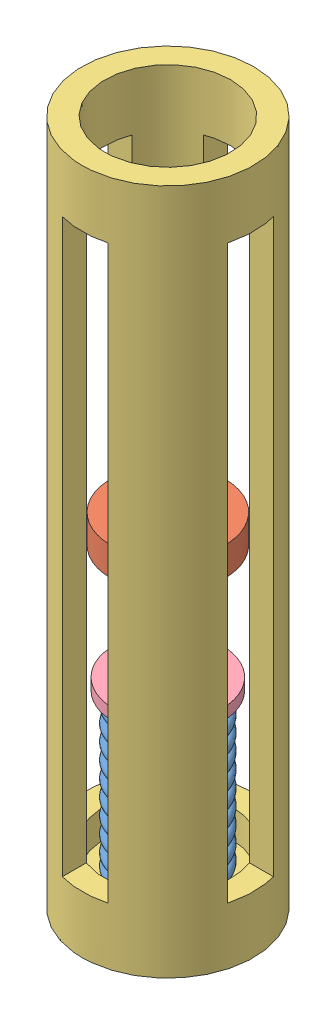
SolidWorks assembly Torpedo Spring Tube 1 inch, configuration Default. Lengths in mm.
Overall size (38.1 152.4 38.1).
4 component instances, 4 part files, 6 mates.
Components (placement in the parent):
- 1986K525_302 STAINLESS STEEL COMPRESSION SPRING-1: 1986K525_302 STAINLESS STEEL COMPRESSION SPRING [1986K525] at (16.8623 -46.4244 245.3297) x (0 0 -1) z (0 -1 0) size (23.69 23.69 38.1)
- MS-P-069 Torpedo Spring Attachment Tube Plunger-1: MS-P-069 Torpedo Spring Attachment Tube Plunger [Default] at (16.8623 22.4097 245.3297) x (1 0 0) z (0 0 -1) size (25.4 31.75 25.4)
- MS-P-0068 Torpedo Blank Tube Spring Attachment-1: MS-P-0068 Torpedo Blank Tube Spring Attachment [Default] at (16.8623 -53.7904 245.3297) size (38.1 152.4 38.1)
- MS-P-0070 Torpedo Spring Plunger Washer-1: MS-P-0070 Torpedo Spring Plunger Washer [Default] at (16.8623 -11.8803 245.3297) size (24.13 2.54 24.13)
Mates (geometry in assembly coordinates):
- Concentric1: concentric anti-aligned: circle of 1986K525_302 STAINLESS STEEL COMPRESSION SPRING-1; circle of MS-P-0068 Torpedo Blank Tube Spring Attachment-1
- Tangent1: tangent: plane of 1986K525_302 STAINLESS STEEL COMPRESSION SPRING-1; plane of MS-P-0068 Torpedo Blank Tube Spring Attachment-1 through (16.8623 -47.4404 245.3297) normal (0 1 0)
- Concentric2: concentric anti-aligned: circle of MS-P-069 Torpedo Spring Attachment Tube Plunger-1; circle of MS-P-0068 Torpedo Blank Tube Spring Attachment-1
- Tangent4: tangent: curve of 1986K525_302 STAINLESS STEEL COMPRESSION SPRING-1; plane of MS-P-069 Torpedo Spring Attachment Tube Plunger-1 through (16.8623 -9.3403 245.3297) normal (0 -1 0)
- Coincident2: coincident anti-aligned: plane of MS-P-069 Torpedo Spring Attachment Tube Plunger-1 through (16.8623 -9.3403 245.3297) normal (0 -1 0); plane of MS-P-0070 Torpedo Spring Plunger Washer-1 through (16.8623 -9.3403 245.3297) normal (0 1 0)
- Concentric3: concentric aligned: cylinder of MS-P-069 Torpedo Spring Attachment Tube Plunger-1 through (16.8623 -9.3403 245.3297) axis (0 1 0) radius 6.35; circle of MS-P-0070 Torpedo Spring Plunger Washer-1
